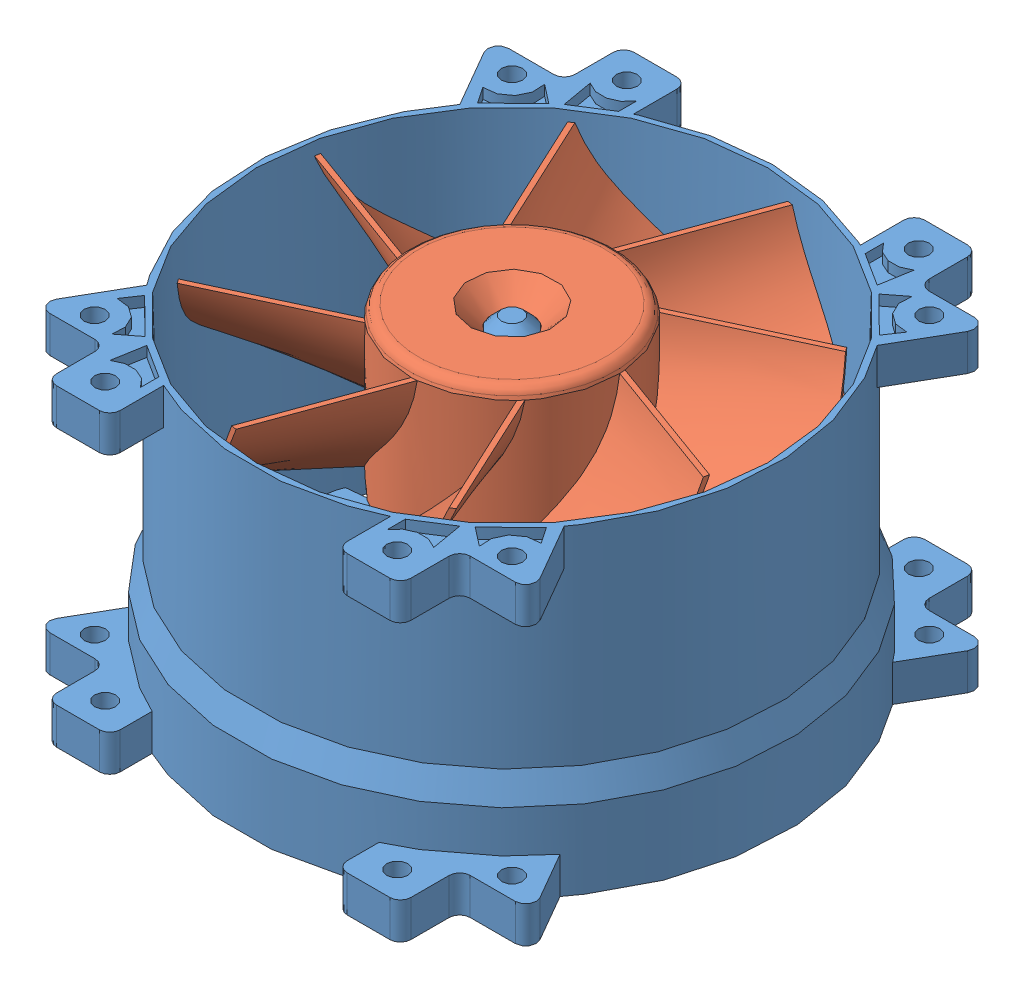
SolidWorks assembly FanAssembly, configuration Default. Lengths in mm.
Overall size (63.67 31.5 63.67).
2 component instances, 2 part files, 2 mates.
Components (placement in the parent):
- fan_housing-1: fan_housing [Default] at origin size (52 30 55.35)
- FanStirr-1: FanStirr [Default] at (0 23 0) x (-0.837169 0 -0.546944) z (0 -1 0) size (46 46 17)
Mates (geometry in assembly coordinates):
- Coincident1: coincident: plane of fan_housing-1 through (-24.5 30 0) normal (0 1 0); plane of FanStirr-1 through (0 30 0) normal (0 1 0)
- Concentric1: concentric aligned: cylinder of fan_housing-1 through (0 35.6569 0) axis (0 -1 0) radius 2; cylinder of FanStirr-1 through (0 31.5007 0) axis (0 -1 0) radius 2
